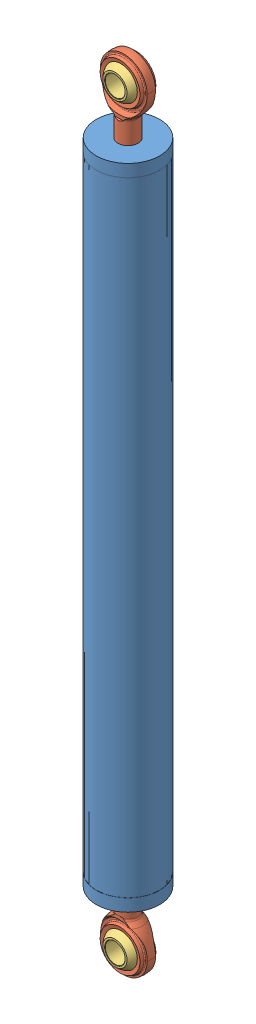
SolidWorks assembly Montagem_Haste_Mag, configuration Valor predeterminado. Lengths in mm.
Overall size (50.8 641.51 50.8).
7 component instances, 3 part files, 6 mates.
Components (placement in the parent):
- Haste_mag-1: Haste_mag [Valor predeterminado] at origin size (50.8 520 50.8)
- 20150831-142919-79084130-1: 20150831-142919-79084130 [Valor predeterminado] at (0 485 0) x (-1 0 0) z (0 1 0) size (39.51 38 85.75)
  - PRODUCT_NAME_1-1: PRODUCT_NAME_1 [Valor predeterminado] at origin size (39.51 38 85.75)
  - PRODUCT_NAME_2-1: PRODUCT_NAME_2 [Valor predeterminado] at origin size (28.58 28.58 28.58)
- 20150831-142919-79084130-2: 20150831-142919-79084130 [Valor predeterminado] at (0 15 0) x (-1 0 0) z (0 -1 0) size (39.51 38 85.75)
  - PRODUCT_NAME_1-1: PRODUCT_NAME_1 [Valor predeterminado] at origin size (39.51 38 85.75)
  - PRODUCT_NAME_2-1: PRODUCT_NAME_2 [Valor predeterminado] at origin size (28.58 28.58 28.58)
Mates (geometry in assembly coordinates):
- Concêntrico13: concentric aligned: cylinder of Haste_mag-1 through (0 0 0) axis (0 -1 0) radius 8; cylinder of 20150831-142919-79084130-1/PRODUCT_NAME_1-1 through (0 505.508 0) axis (0 -1 0) radius 8
- Distância1: distance = 25 mm anti-aligned: plane of Haste_mag-1 through (25.4 510 0) normal (0 1 0); plane of 20150831-142919-79084130-1/PRODUCT_NAME_1-1 through (-3.492 485 0) normal (0 -1 0)
- Concêntrico14: concentric anti-aligned: cylinder of Haste_mag-1 through (0 0 0) axis (0 -1 0) radius 8; cylinder of 20150831-142919-79084130-2/PRODUCT_NAME_1-1 through (0 -5.508 0) axis (0 1 0) radius 8
- Distância2: distance = 25 mm anti-aligned: plane of 20150831-142919-79084130-2/PRODUCT_NAME_1-1 through (-3.492 15 0) normal (0 1 0); plane of Haste_mag-1 through (25.4 -10 0) normal (0 -1 0)
- Coincidente3: coincident anti-aligned: unknown of ?
- Coincidente4: coincident aligned: unknown of ?
